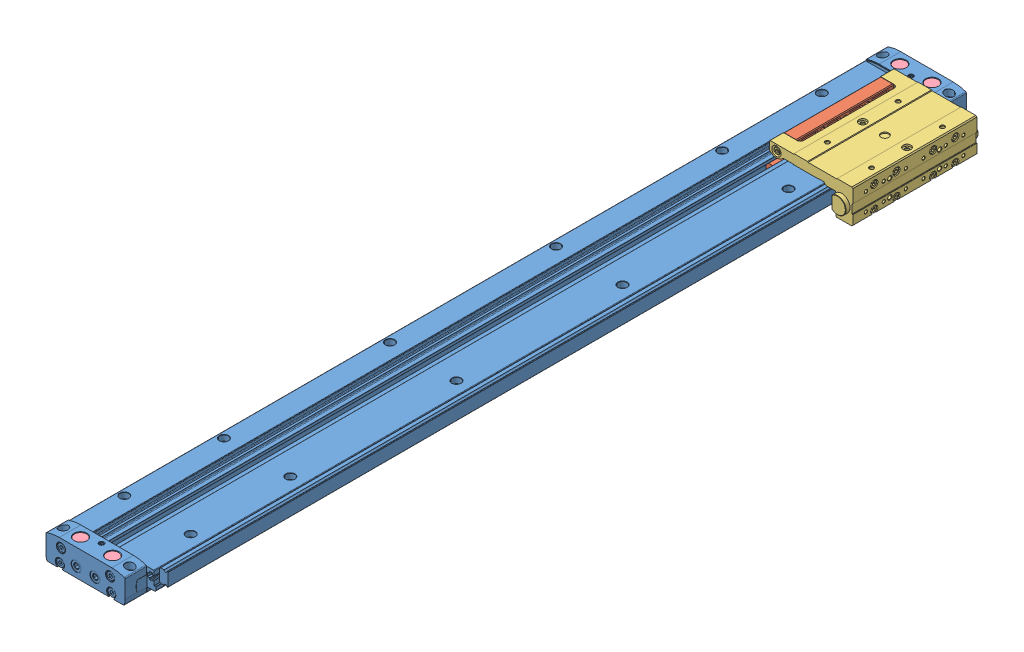
SolidWorks assembly 5074948 DLGF-KF-20-600-PPSA---(0), configuration Default. Lengths in mm.
Overall size (105 32 760).
7 component instances, 4 part files, 18 mates.
Components (placement in the parent):
- 8063799 DLGF-20-KF-600---(G)-1: 8063799 DLGF-20-KF-600---(G) [Default] at origin size (85.5 24 760)
- 4002773 DLGF-20-1: 4002773 DLGF-20 [Default] at (0 6.5 -300) size (12 25 120)
- 8072429 DLGF-20-1: 8072429 DLGF-20 [Default] at (42 32 -300) size (75 30.5 119.8)
- 8070146 DLGF-20_25-1: 8070146 DLGF-20_25 [Default] at (14.5 19 -370) size (11 4.5 11)
- 8070146 DLGF-20_25-2: 8070146 DLGF-20_25 [Default] at (14.5 19 370) size (11 4.5 11)
- 8070146 DLGF-20_25-3: 8070146 DLGF-20_25 [Default] at (-14.5 19 -370) size (11 4.5 11)
- 8070146 DLGF-20_25-4: 8070146 DLGF-20_25 [Default] at (-14.5 19 370) size (11 4.5 11)
Mates (geometry in assembly coordinates):
- LimitDistance1: limit distance = 600 mm anti-aligned: plane of 8063799 DLGF-20-KF-600---(G)-1 through (0 0 300) normal (0 0 -1); plane of 4002773 DLGF-20-1 through (0 6.5 -300) normal (0 0 1)
- Coincident1: coincident anti-aligned: line of 8063799 DLGF-20-KF-600---(G)-1 through (0 11.75 -80.9) axis (0 0 1); line of 4002773 DLGF-20-1 through (0 11.75 -219.1) axis (0 0 -1)
- Angle3: planar angle = 0 rad aligned: plane of 4002773 DLGF-20-1 through (0 6.5 -300) normal (1 0 0); plane of 8063799 DLGF-20-KF-600---(G)-1 through (0 0 0) normal (1 0 0)
- Distance1: distance = 0 mm anti-aligned: plane of 4002773 DLGF-20-1 through (0 6.5 -300) normal (0 0 -1); plane of 8072429 DLGF-20-1 through (42 32 -300) normal (0 0 1)
- Coincident2: coincident anti-aligned: line of 4002773 DLGF-20-1 through (0 25.8 -380.9) axis (0 0 1); line of 8072429 DLGF-20-1 through (0 25.8 -219.1) axis (0 0 -1)
- Angle6: planar angle = 0 rad aligned: plane of 8072429 DLGF-20-1 through (0 32 -300) normal (1 0 0); plane of 4002773 DLGF-20-1 through (0 6.5 -300) normal (1 0 0)
- Distance2: distance = 0 mm anti-aligned: plane of 8063799 DLGF-20-KF-600---(G)-1 through (0 19 0) normal (0 1 0); plane of 8070146 DLGF-20_25-1 through (14.5 19 -370) normal (0 -1 0)
- Coincident3: coincident anti-aligned: line of 8063799 DLGF-20-KF-600---(G)-1 through (14.5 50 -370) axis (0 -1 0); line of 8070146 DLGF-20_25-1 through (14.5 -31 -370) axis (0 1 0)
- Angle9: planar angle = 0 rad aligned: plane of 8070146 DLGF-20_25-1 through (14.5 19 -370) normal (1 0 0); plane of 8063799 DLGF-20-KF-600---(G)-1 through (14.5 0 0) normal (1 0 0)
- Distance3: distance = 0 mm anti-aligned: plane of 8063799 DLGF-20-KF-600---(G)-1 through (0 19 0) normal (0 1 0); plane of 8070146 DLGF-20_25-2 through (14.5 19 370) normal (0 -1 0)
- Coincident4: coincident anti-aligned: line of 8063799 DLGF-20-KF-600---(G)-1 through (14.5 50 370) axis (0 -1 0); line of 8070146 DLGF-20_25-2 through (14.5 -31 370) axis (0 1 0)
- Angle12: planar angle = 0 rad aligned: plane of 8070146 DLGF-20_25-2 through (14.5 19 370) normal (1 0 0); plane of 8063799 DLGF-20-KF-600---(G)-1 through (14.5 0 0) normal (1 0 0)
- Distance4: distance = 0 mm anti-aligned: plane of 8063799 DLGF-20-KF-600---(G)-1 through (0 19 0) normal (0 1 0); plane of 8070146 DLGF-20_25-3 through (-14.5 19 -370) normal (0 -1 0)
- Coincident5: coincident anti-aligned: line of 8063799 DLGF-20-KF-600---(G)-1 through (-14.5 50 -370) axis (0 -1 0); line of 8070146 DLGF-20_25-3 through (-14.5 -31 -370) axis (0 1 0)
- Angle15: planar angle = 0 rad aligned: plane of 8070146 DLGF-20_25-3 through (-14.5 19 -370) normal (1 0 0); plane of 8063799 DLGF-20-KF-600---(G)-1 through (-14.5 0 0) normal (1 0 0)
- Distance5: distance = 0 mm anti-aligned: plane of 8063799 DLGF-20-KF-600---(G)-1 through (0 19 0) normal (0 1 0); plane of 8070146 DLGF-20_25-4 through (-14.5 19 370) normal (0 -1 0)
- Coincident6: coincident anti-aligned: line of 8063799 DLGF-20-KF-600---(G)-1 through (-14.5 50 370) axis (0 -1 0); line of 8070146 DLGF-20_25-4 through (-14.5 -31 370) axis (0 1 0)
- Angle18: planar angle = 0 rad aligned: plane of 8070146 DLGF-20_25-4 through (-14.5 19 370) normal (1 0 0); plane of 8063799 DLGF-20-KF-600---(G)-1 through (-14.5 0 0) normal (1 0 0)
